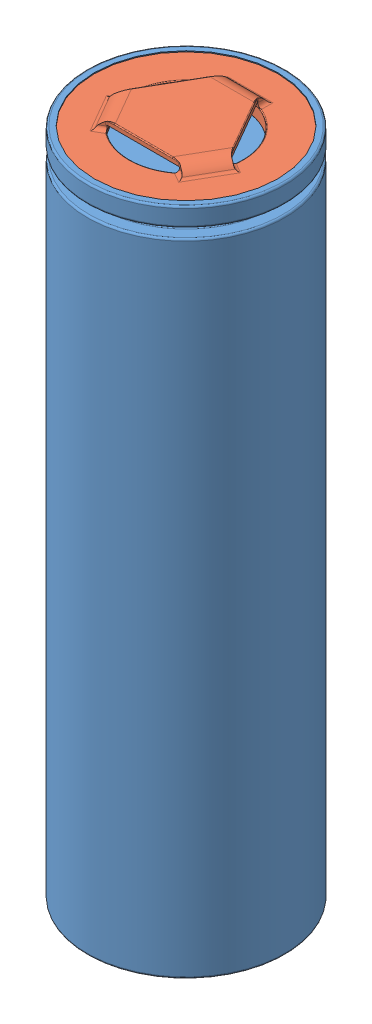
SolidWorks assembly 21700 cell, configuration Default. Lengths in mm.
Overall size (21 72.01 21).
2 component instances, 2 part files, 2 mates.
Components (placement in the parent):
- Part1-1: Part1 [Default] at (33.3086 7.6925 70.8533) size (21 71 21)
- Part2-1: Part2 [Default] at (33.3086 77.1925 70.8533) size (20 2.51 20)
Mates (geometry in assembly coordinates):
- Coincident1: coincident anti-aligned: plane of Part1-1 through (33.3086 77.1925 70.8533) normal (0 1 0); plane of Part2-1 through (33.3086 77.1925 70.8533) normal (0 -1 0)
- Concentric1: concentric anti-aligned: cylinder of Part1-1 through (33.3086 77.1925 70.8533) axis (0 1 0) radius 9.75; cylinder of Part2-1 through (33.3086 78.5925 70.8533) axis (0 -1 0) radius 10
